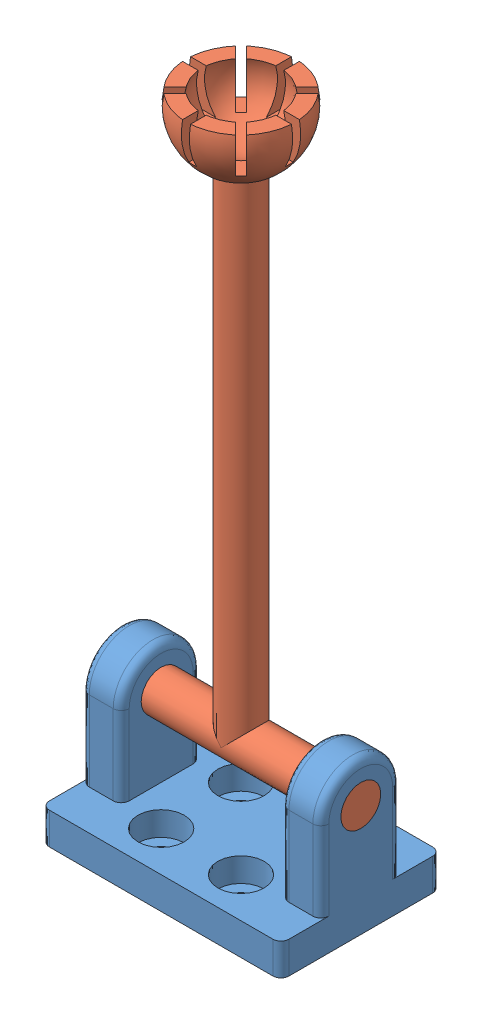
SolidWorks assembly Assemblage1, configuration Défaut. Lengths in mm.
Overall size (30 84.04 20).
2 component instances, 2 part files, 3 mates.
Components (placement in the parent):
- support-fourchette-chc_m3-1: support-fourchette-chc_m3 [Défaut] at (-2.163 3.1541 30) size (30 19 20)
- bras-cavite-pivot-1: bras-cavite-pivot [Défaut] at (-2.163 71.6925 30) x (0 0 1) z (-1 0 0) size (13.96 72.54 30)
Mates (geometry in assembly coordinates):
- Coaxiale1: concentric: cylinder of support-fourchette-chc_m3-1 through (12.837 3.1541 30) axis (-1 0 0) radius 2.5; cylinder of bras-cavite-pivot-1 through (-17.163 3.1541 30) axis (1 0 0) radius 2.5
- Coïncidente1: coincident: plane of support-fourchette-chc_m3-1 through (12.837 3.1541 30) normal (1 0 0); plane of bras-cavite-pivot-1 through (12.837 3.1541 30) normal (1 0 0)
- Parallèle1: parallel anti-aligned: plane of support-fourchette-chc_m3-1 through (-2.163 -10.8459 30) normal (0 -1 0); plane of bras-cavite-pivot-1 through (-2.163 73.1925 25.1256) normal (0 1 0)
